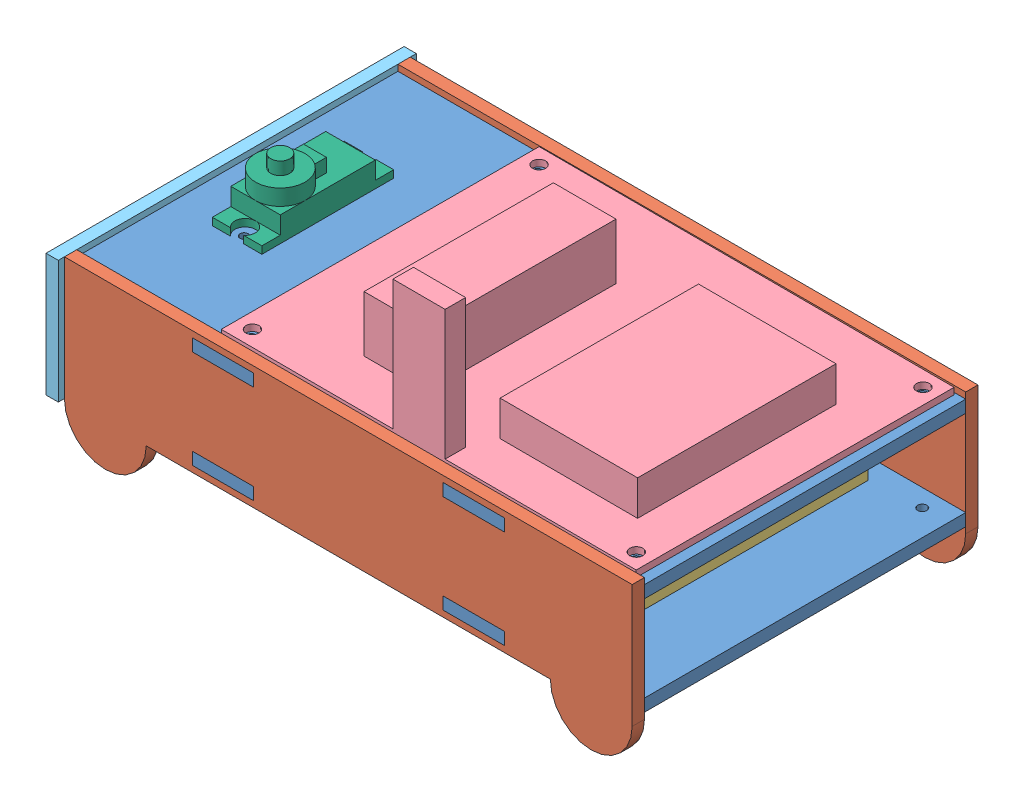
SolidWorks assembly proto_box, configuration Default. Lengths in mm.
Overall size (141.7 71.77 87.47).
8 component instances, 6 part files, 18 mates.
Components (placement in the parent):
- box_tb-1: box_tb [Default] at (-24.4925 97.1577 0.6543) x (1 0 0) z (0 -1 0) size (141.69 84.47 3)
- box_tb-2: box_tb [Default] at (-24.4925 73.1577 0.6543) x (1 0 0) z (0 -1 0) size (141.69 84.47 3)
- box_sides-1: box_sides [Default] at (-61.0504 59.6986 -9.3257) size (141.7 40 3)
- box_sides-2: box_sides [Default] at (-61.0504 59.6986 72.1443) size (141.7 40 3)
- batterypack-1: batterypack [Default] at (58.9177 73.1577 66.4872) size (64 18.86 67.65)
- carrierboard-1: carrierboard [Default] at (70.9659 97.1577 49.2918) x (0.999997 0 0.002293) z (-0.002293 0 0.999997) size (101.6 33.27 77.47)
- box_front-1: box_front [Default] at (-61.0404 68.6577 -10.8257) x (0 0 1) z (-1 0 0) size (87.47 30 3)
- servo-1: servo [Default] at (-44.9904 81.6577 32.9143) x (0 0 1) z (-1 0 0) size (32.2 28.6 12.1)
Mates (geometry in assembly coordinates):
- Coincident1: coincident anti-aligned: plane of box_tb-2 through (-14.8104 70.1577 72.1443) normal (0 0 1); plane of box_sides-2 through (-51.0504 68.6577 72.1443) normal (0 0 -1)
- Coincident2: coincident anti-aligned: plane of box_tb-2 through (46.4196 70.1577 -6.3257) normal (0 0 -1); plane of box_sides-1 through (-51.0504 68.6577 -6.3257) normal (0 0 1)
- Coincident3: coincident anti-aligned: plane of box_tb-2 through (-24.4925 73.1577 0.6543) normal (0 1 0); plane of box_sides-2 through (-29.8104 73.1577 72.1443) normal (0 -1 0)
- Coincident4: coincident anti-aligned: plane of box_tb-2 through (46.4196 70.1577 75.1443) normal (1 0 0); plane of box_sides-2 through (46.4196 73.1577 72.1443) normal (-1 0 0)
- Coincident5: coincident anti-aligned: plane of box_tb-2 through (-24.4925 73.1577 0.6543) normal (0 1 0); plane of box_sides-1 through (-29.8104 73.1577 -9.3257) normal (0 -1 0)
- Coincident6: coincident anti-aligned: plane of box_tb-2 through (-14.8104 70.1577 -9.3257) normal (1 0 0); plane of box_sides-1 through (-14.8104 73.1577 -9.3257) normal (-1 0 0)
- Coincident7: coincident anti-aligned: plane of box_tb-1 through (-14.8104 94.1577 72.1443) normal (0 0 1); plane of box_sides-2 through (-51.0504 68.6577 72.1443) normal (0 0 -1)
- Coincident8: coincident anti-aligned: plane of box_tb-1 through (-24.4925 97.1577 0.6543) normal (0 1 0); plane of box_sides-2 through (-29.8104 97.1577 72.1443) normal (0 -1 0)
- Coincident9: coincident anti-aligned: plane of box_tb-1 through (-14.8104 94.1577 75.1443) normal (1 0 0); plane of box_sides-2 through (-14.8104 97.1577 72.1443) normal (-1 0 0)
- Coincident10: coincident anti-aligned: plane of box_tb-2 through (-24.4925 73.1577 0.6543) normal (0 1 0); plane of batterypack-1 through (58.9177 73.1577 66.4872) normal (0 -1 0)
- Coincident12: coincident anti-aligned: plane of box_tb-1 through (-24.4925 97.1577 0.6543) normal (0 1 0); plane of carrierboard-1 through (70.9659 97.1577 49.2918) normal (0 -1 0)
- Coincident13: coincident anti-aligned: plane of box_tb-1 through (-61.0404 94.1577 40.4093) normal (-1 0 0); plane of box_front-1 through (-61.0404 68.6577 -10.8257) normal (1 0 0)
- Coincident14: coincident anti-aligned: plane of box_sides-2 through (-51.0504 68.6577 75.1443) normal (0 0 1); plane of box_front-1 through (-61.0404 93.6577 75.1443) normal (0 0 -1)
- Coincident15: coincident anti-aligned: plane of box_sides-2 through (-64.0504 78.6577 75.1443) normal (0 -1 0); plane of box_front-1 through (-61.0404 78.6577 72.1443) normal (0 1 0)
- Concentric1: concentric anti-aligned: circle of box_tb-1; circle of carrierboard-1
- Coincident16: coincident anti-aligned: plane of box_tb-1 through (-51.0404 97.1577 44.5143) normal (1 0 0); plane of servo-1 through (-51.0404 103.2577 21.3143) normal (-1 0 0)
- Coincident17: coincident anti-aligned: plane of box_tb-1 through (-51.0404 97.1577 21.3143) normal (0 0 1); plane of servo-1 through (-38.9404 103.2577 21.3143) normal (0 0 -1)
- Coincident18: coincident anti-aligned: plane of box_tb-1 through (-24.4925 97.1577 0.6543) normal (0 1 0); plane of servo-1 through (-44.9904 97.1577 32.9143) normal (0 -1 0)
